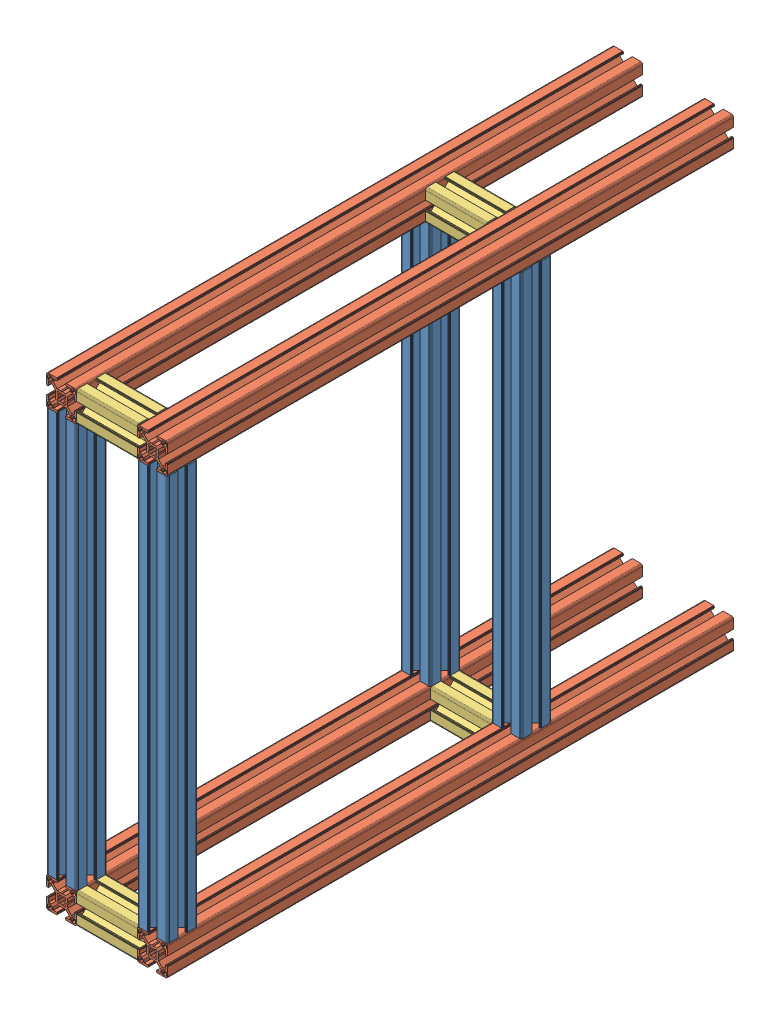
SolidWorks assembly module7_frame_v1.0, configuration Default. Lengths in mm.
Overall size (120 460 560).
12 component instances, 3 part files, 35 mates.
Components (placement in the parent):
- Profile_30x30mm_400mm-1: Profile_30x30mm_400mm [Default] x (1 0 0) z (0 -1 0) size (30 30 400)
- Profile_30x30mm_400mm-3: Profile_30x30mm_400mm [Default] at (-90 0 0) x (1 0 0) z (0 -1 0) size (30 30 400)
- profile_30x30mm_560mm-8: profile_30x30mm_560mm [Default] at (0 -30 30) size (30 30 560)
- profile_30x30mm_560mm-10: profile_30x30mm_560mm [Default] at (-90 -30 30) size (30 30 560)
- profile_30x30mm_560mm-6: profile_30x30mm_560mm [Default] at (-90 400 30) size (30 30 560)
- Profile_30x30mm_400mm-4: Profile_30x30mm_400mm [Default] at (30 400 -350) x (-1 0 0) z (0 1 0) size (30 30 400)
- profile_30x30mm_560mm-9: profile_30x30mm_560mm [Default] at (0 400 30) size (30 30 560)
- Profile_30x30mm_60mm-10: Profile_30x30mm_60mm [Default] at (0 400 30) x (0 0 -1) z (1 0 0) size (30 30 60)
- Profile_30x30mm_60mm-4: Profile_30x30mm_60mm [Default] at (0 400 -315) x (0 0 -1) z (1 0 0) size (30 30 60)
- Profile_30x30mm_60mm-7: Profile_30x30mm_60mm [Default] at (0 0 30) x (0 -1 0) z (1 0 0) size (30 30 60)
- Profile_30x30mm_60mm-9: Profile_30x30mm_60mm [Default] at (0 -30 -320) x (0 0 -1) z (1 0 0) size (30 30 60)
- Profile_30x30mm_400mm-5: Profile_30x30mm_400mm [Default] at (-90 0 -350) x (1 0 0) z (0 -1 0) size (30 30 400)
Mates (geometry in assembly coordinates):
- Coincident1: coincident: plane of Profile_30x30mm_400mm-1 through (0 400 0) normal (0 1 0); plane of ? through (-224.6126 400 0) normal (0 1 0)
- Coincident7: coincident: plane of Profile_30x30mm_400mm-1 through (10.25 400 30) normal (0 0 1); plane of ? through (-196.6126 400 30) normal (0 0 1)
- Coincident25: coincident: plane of profile_30x30mm_560mm-8 through (0 -30 30) normal (0 0 1); plane of ? through (-224.6126 -30 30) normal (0 0 1)
- Coincident26: coincident: plane of ? through (-224.6126 -30 30) normal (0 0 1); plane of ? through (-224.6126 400 30) normal (0 0 1)
- Coincident27: coincident: plane of ? through (-194.6126 -10.25 -530) normal (1 0 0); plane of ? through (-194.6126 419.75 -530) normal (1 0 0)
- Coincident30: coincident: plane of profile_30x30mm_560mm-8 through (10.25 0 -530) normal (0 1 0); plane of ? through (-214.3626 0 -530) normal (0 1 0)
- Coincident32: coincident: plane of assembly; plane of assembly; plane of Profile_30x30mm_400mm-1 through (30 400 2) normal (1 0 0); plane of profile_30x30mm_560mm-8 through (30 -28 -530) normal (1 0 0)
- Coincident35: coincident: plane of ? through (-224.6126 400 10.25) normal (-1 0 0); plane of ? through (-224.6126 428 -530) normal (-1 0 0)
- Coincident69: coincident: plane of assembly through (0 0 0) normal (0 1 0); plane of Profile_30x30mm_400mm-1 through (0 0 0) normal (0 -1 0); plane of assembly
- Coincident70: coincident: plane of assembly through (0 0 0) normal (0 0 1); plane of Profile_30x30mm_400mm-1 through (0 0 0) normal (0 0 1); plane of assembly
- Coincident71: coincident: plane of assembly through (0 0 0) normal (1 0 0); plane of Profile_30x30mm_400mm-1 through (0 0 0) normal (1 0 0); plane of assembly
- Coincident81: coincident: plane of assembly; plane of assembly; plane of Profile_30x30mm_400mm-1 through (30 400 19.75) normal (1 0 0); plane of profile_30x30mm_560mm-9 through (30 419.75 -530) normal (1 0 0)
- Distance36: distance = 30 mm: plane of assembly; plane of assembly; plane of Profile_30x30mm_400mm-1 through (0 0 0) normal (0 -1 0); plane of profile_30x30mm_560mm-8 through (19.75 -30 -530) normal (0 -1 0)
- Distance37: distance = 30 mm: plane of assembly; plane of assembly; plane of Profile_30x30mm_400mm-1 through (19.75 400 0) normal (0 0 -1); plane of profile_30x30mm_560mm-8 through (0 -30 30) normal (0 0 1)
- Distance38: distance = 30 mm: plane of assembly; plane of assembly; plane of Profile_30x30mm_400mm-1 through (19.75 400 0) normal (0 0 -1); plane of profile_30x30mm_560mm-9 through (0 400 30) normal (0 0 1)
- Distance39: distance = 30 mm: plane of assembly; plane of assembly; plane of Profile_30x30mm_400mm-3 through (-90 400 0) normal (0 1 0); plane of profile_30x30mm_560mm-6 through (-62 430 -530) normal (0 1 0)
- Distance40: distance = 30 mm: plane of assembly; plane of assembly; plane of Profile_30x30mm_400mm-1 through (0 400 0) normal (0 1 0); plane of profile_30x30mm_560mm-9 through (10.25 430 -530) normal (0 1 0)
- Coincident114: coincident: plane of assembly; plane of assembly; plane of profile_30x30mm_560mm-8 through (28 0 -530) normal (0 1 0); plane of Profile_30x30mm_400mm-4 through (30 0 -350) normal (0 -1 0)
- Coincident115: coincident: plane of assembly; plane of assembly; plane of profile_30x30mm_560mm-8 through (30 -10.25 -530) normal (1 0 0); plane of Profile_30x30mm_400mm-4 through (30 0 -339.75) normal (1 0 0)
- Coincident118: coincident: point of ?; plane of ? through (-194.6126 400 -315) normal (-1 0 0)
- Coincident119: coincident: plane of ? through (-194.6126 400 30) normal (-1 0 0); plane of ? through (-194.6126 400 -315) normal (-1 0 0)
- Coincident120: coincident: plane of ? through (-194.6126 419.75 -530) normal (1 0 0); plane of ? through (-194.6126 400 -315) normal (-1 0 0)
- Coincident123: coincident: plane of ? through (-194.6126 400 28) normal (0 -1 0); plane of ? through (-194.6126 400 -334.75) normal (0 -1 0)
- Coincident126: coincident: plane of ? through (-214.3626 430 -530) normal (0 1 0); plane of ? through (-194.6126 430 -325.25) normal (0 1 0)
- Coincident141: coincident: plane of ? through (-194.6126 -19.75 30) normal (0 0 1); plane of ? through (-224.6126 -30 30) normal (0 0 1)
- Coincident142: coincident: plane of ? through (-222.6126 -30 -530) normal (0 -1 0); plane of ? through (-194.6126 -30 28) normal (0 -1 0)
- Coincident143: coincident: plane of ? through (-194.6126 -28 -530) normal (1 0 0); plane of ? through (-194.6126 0 30) normal (-1 0 0)
- Distance45: distance = 185 mm: plane of assembly; plane of assembly; plane of Profile_30x30mm_60mm-4 through (-60 419.75 -345) normal (0 0 -1); plane of profile_30x30mm_560mm-6 through (-90 400 -530) normal (0 0 -1)
- Coincident163: coincident: plane of ? through (-194.6126 -10.25 -530) normal (1 0 0); plane of ? through (-194.6126 -30 -320) normal (-1 0 0)
- Distance50: distance = 180 mm: plane of assembly; plane of assembly; plane of Profile_30x30mm_60mm-9 through (-60 -28 -350) normal (0 0 -1); plane of profile_30x30mm_560mm-10 through (-90 -30 -530) normal (0 0 -1)
- Coincident186: coincident: plane of ? through (-196.6126 0 -530) normal (0 1 0); plane of ? through (-224.6126 0 -350) normal (0 -1 0)
- Coincident187: coincident: plane of ? through (-224.6126 -2 -530) normal (-1 0 0); plane of ? through (-224.6126 400 -339.75) normal (-1 0 0)
- Coincident188: coincident: plane of ? through (-194.6126 -19.75 -320) normal (0 0 1); plane of ? through (-196.6126 400 -320) normal (0 0 1)
- Coincident189: coincident: plane of Profile_30x30mm_400mm-4 through (2 0 -320) normal (0 0 1); plane of ? through (-194.6126 -19.75 -320) normal (0 0 1)
- Coincident190: coincident: plane of assembly; plane of assembly; plane of profile_30x30mm_560mm-9 through (0 428 -530) normal (-1 0 0); plane of Profile_30x30mm_60mm-4 through (0 400 -315) normal (1 0 0)
